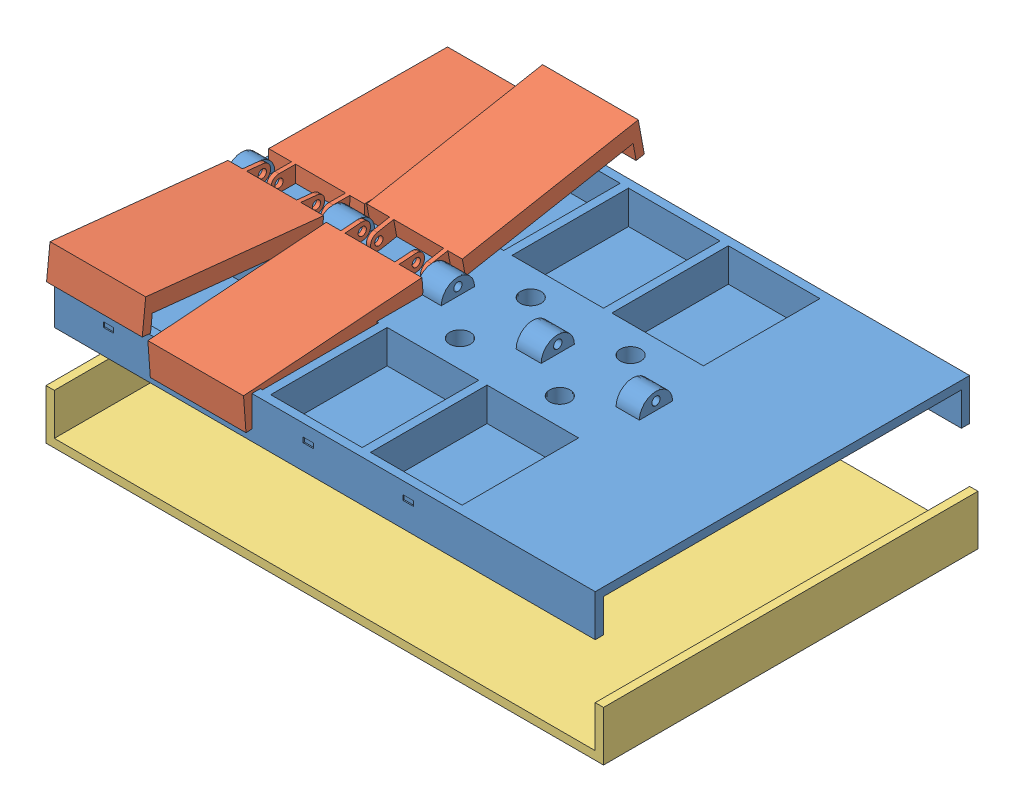
SolidWorks assembly 装配体1, configuration 默认. Lengths in mm.
Overall size (159.48 47.63 104.87).
6 component instances, 3 part files, 11 mates.
Components (placement in the parent):
- 零件1-1: 零件1 [默认] at (-88.3227 1.3962 175) size (159.48 14 104.87)
- 零件2-1: 零件2 [默认] at (-64.3227 13.3962 130) x (0 0.104119 0.994565) z (-1 0 0) size (49 8 23)
- 零件2-2: 零件2 [默认] at (-86.3227 13.3962 130) x (0 -0.007915 -0.999969) z (1 0 0) size (49 8 23)
- outsideBox-1: outsideBox [默认] at (-26.1737 -21.6967 130) x (0 0 -1) z (-1 0 0) size (90 12 134)
- 零件2-3: 零件2 [默认] at (-62.3227 13.3962 130) x (0 0.182356 -0.983232) z (1 0 0) size (49 8 23)
- 零件2-15: 零件2 [默认] at (-40.3227 13.3962 130) x (0 -0.073965 0.997261) z (-1 0 0) size (49 8 23)
Mates (geometry in assembly coordinates):
- 同心1: concentric aligned: circle of 零件1-1; circle of 零件2-1
- 重合4: coincident anti-aligned: plane of 零件1-1 through (-84.3227 1.3962 175) normal (1 0 0); plane of 零件2-1 through (-84.3227 13.3962 130) normal (-1 0 0)
- 同心2: concentric aligned: circle of 零件1-1; circle of 零件2-2
- 重合6: coincident anti-aligned: plane of 零件1-1 through (-66.3227 1.3962 175) normal (-1 0 0); plane of 零件2-2 through (-66.3227 13.3962 130) normal (1 0 0)
- 平行2: parallel anti-aligned: plane of 零件1-1 through (-78.694 9.3962 173) normal (0 -1 0); plane of outsideBox-1 through (-26.1737 -21.6967 130) normal (0 1 0)
- 重合9: coincident aligned: line of 零件1-1 through (41.6773 11.3962 175) axis (0 -1 0); line of outsideBox-1 through (41.6773 -11.6967 175) axis (0 -1 0)
- 重合10: coincident aligned: line of 零件1-1 through (41.6773 11.3962 85) axis (0 -1 0); line of outsideBox-1 through (41.6773 -11.6967 85) axis (0 -1 0)
- 同心3: concentric anti-aligned: circle of 零件1-1; circle of 零件2-3
- 重合12: coincident anti-aligned: plane of 零件1-1 through (-42.3227 1.3962 175) normal (-1 0 0); plane of 零件2-3 through (-42.3227 13.3962 130) normal (1 0 0)
- 同心4: concentric anti-aligned: circle of 零件2-3; circle of 零件2-15
- 重合14: coincident anti-aligned: plane of 零件1-1 through (-60.3227 1.3962 175) normal (1 0 0); plane of 零件2-15 through (-60.3227 13.3962 130) normal (-1 0 0)
